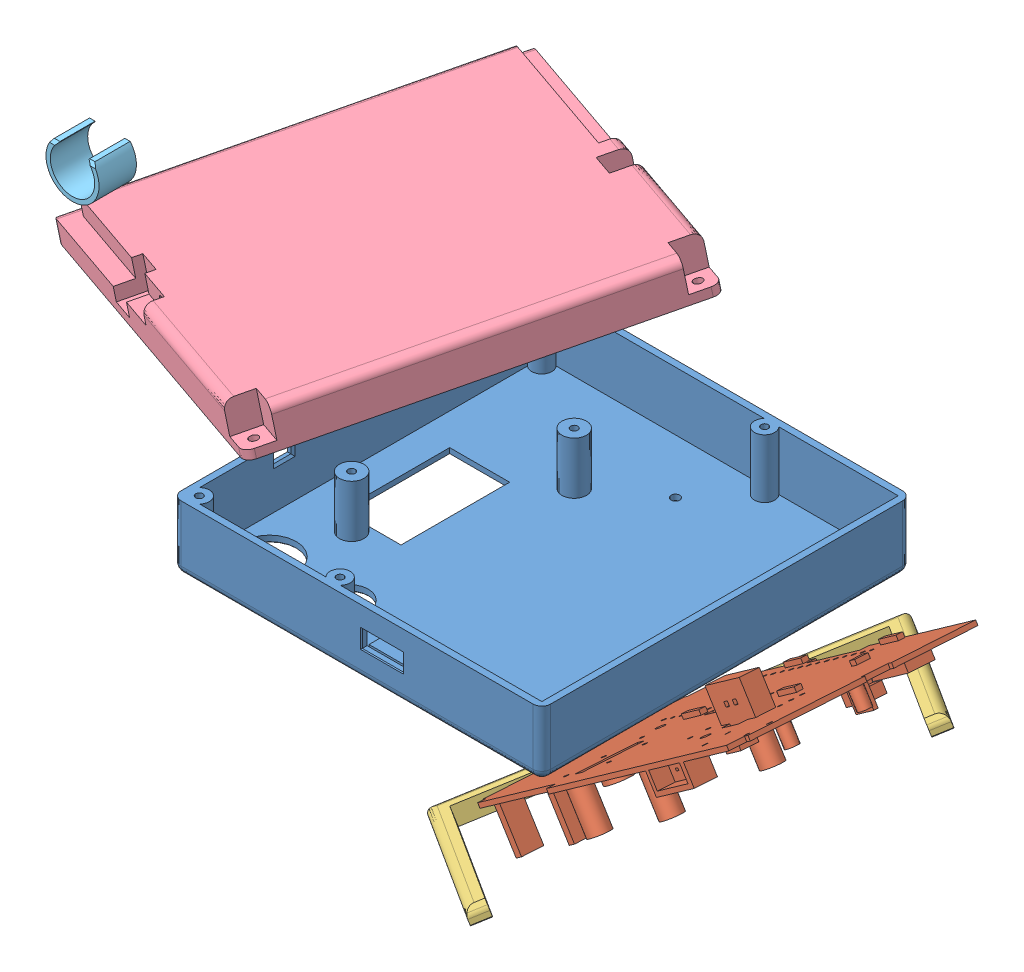
SolidWorks assembly 定时喝水打印件, configuration 默认. Lengths in mm.
Overall size (137.22 154.73 151.02).
5 component instances, 5 part files, 0 mates.
Components (placement in the parent):
- 前壳-1: 前壳 [默认] at (4.4608 -11.5235 85) size (85 15 85)
- 压板-1: 压板 [默认] at (28.2091 -36.7929 67.6574) x (0.815677 0.578499 0.003188) z (0.577818 -0.814961 0.044334) size (75 55 18.1)
- 支架-1: 支架 [默认] at (-72.3981 -79.1144 -34.9318) x (0.791513 0.199003 0.577844) z (-0.34215 0.92773 0.149167) size (42.5 85 4)
- 后壳-1: 后壳 [默认] at (-107.264 35.8716 31.1131) x (0.907532 0.130834 0.399084) z (-0.172235 0.982598 0.069538) size (85 85 9)
- 红外圈套-1: 红外圈套 [默认] at (79.2439 185.4617 127.0639) size (12.2 10.03 8.6)
